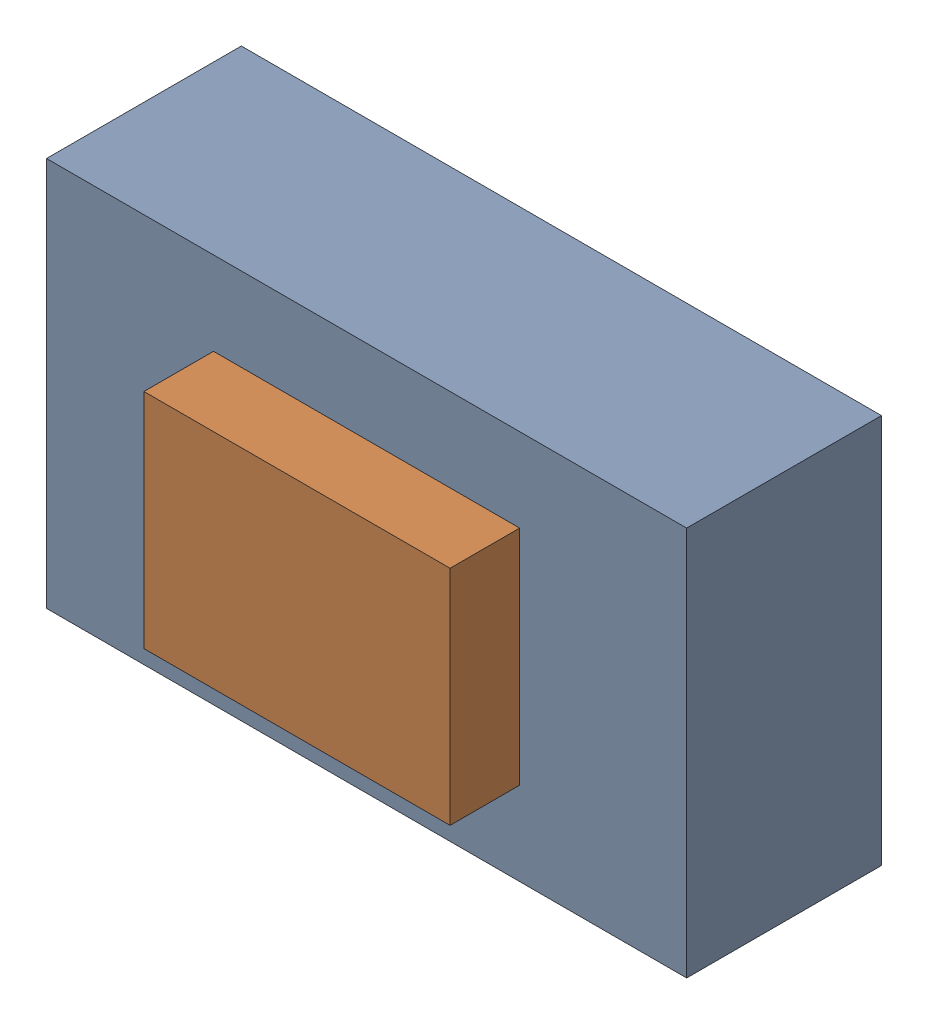
SolidWorks assembly SW3, configuration Default. Lengths in mm.
Overall size (4.6 2.8 1.9).
4 component instances, 2 part files, 0 mates.
Components (placement in the parent):
- 870942880-1: 870942880 [Default] at (44.9573 2.8427 0) size (4.6 2.8 1.4)
  - Extruded_21-1: Extruded_21 [Default] at origin size (4.6 2.8 1.4)
- 870943040-1: 870943040 [Default] at (44.9572 2.8426 1.4) size (2.2 1.6 0.5)
  - Extruded_22-1: Extruded_22 [Default] at origin size (2.2 1.6 0.5)
